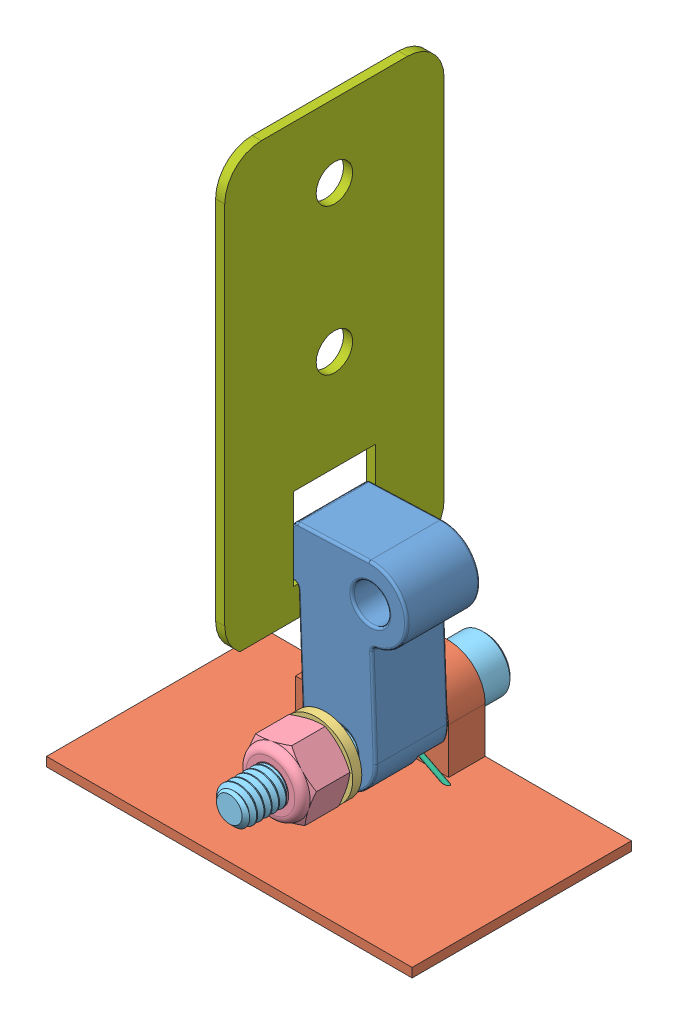
SolidWorks assembly ArrayLock, configuration Default. Lengths in mm.
Overall size (63.5 105.25 45.75).
7 component instances, 7 part files, 13 mates.
Components (placement in the parent):
- ArrayPin(V1)-1: ArrayPin(V1) [Default] at (-53.8648 34.9117 1.7367) x (0.999277 0.038028 0) z (0 0 1) size (25.4 36.51 12.7)
- pinstand-1: pinstand [Default] at (-85.6148 25.3867 -17.3133) size (63.5 15.88 38.1)
- pt25xpt5washer-1: pt25xpt5washer [Default] at (-53.8648 34.9117 5.7161) x (-0.497305 -0.867576 0) z (0 0 -1) size (12.7 12.7 1.59)
- 90630A110_High-Strength Steel Nylon-Insert Locknut-1: 90630A110_High-Strength Steel Nylon-Insert Locknut [90630A110] at (-53.8648 34.9117 5.7161) x (-0.951087 0.308922 0) z (0.308922 0.951087 0) size (11.11 8.31 12.83)
- 90128A251_Zinc-Plated Alloy Steel Socket Head Screw-2: 90128A251_Zinc-Plated Alloy Steel Socket Head Screw [90128A251] at (-53.8648 34.9117 -1.4383) x (-0.999187 0.040322 0) z (0 0 -1) size (9.53 9.53 45.23)
- 9271K274_Torsion Spring-1: 9271K274_Torsion Spring [9271K274] at (-53.9119 35.5553 -9.8575) x (0.001959 -0.028703 -0.999586) z (0.884392 -0.466499 0.015129) size (5.5 24.74 42.2)
- Snapmount-1: Snapmount [Default] at (-63.3898 48.5361 13.643) x (0 0 -1) z (1 0 0) size (38.1 76.2 1.59)
Mates (geometry in assembly coordinates):
- Concentric3: concentric anti-aligned: cylinder of ArrayPin(V1)-1 through (-53.8648 34.9117 -10.9633) axis (0 0 -1) radius 3.175; cylinder of pt25xpt5washer-1 through (-53.8648 34.9117 4.1286) axis (0 0 1) radius 3.175
- Concentric5: concentric anti-aligned: cylinder of pt25xpt5washer-1 through (-53.8648 34.9117 4.1286) axis (0 0 1) radius 6.35; cylinder of 90630A110_High-Strength Steel Nylon-Insert Locknut-1 through (-53.8648 34.9117 12.4069) axis (0 0 -1) radius 2.6987
- Coincident17: coincident anti-aligned: plane of ArrayPin(V1)-1 through (-48.4249 58.9485 -10.9633) normal (0 0 -1); plane of pinstand-1 through (-53.8648 34.9117 -10.9633) normal (0 0 1)
- Concentric8: concentric anti-aligned: cylinder of ArrayPin(V1)-1 through (-53.8648 34.9117 -10.9633) axis (0 0 1) radius 3.175; cylinder of pinstand-1 through (-53.8648 34.9117 -10.9633) axis (0 0 -1) radius 3.175
- Parallel3: parallel anti-aligned: plane of ArrayPin(V1)-1 through (-59.6191 60.8821 -6.2008) normal (0.038028 -0.999277 0); plane of 9271K274_Torsion Spring-1 through (-59.2372 60.8654 -6.5818) normal (-0.038028 0.999277 0)
- Distance4: distance = 0.0312 mm anti-aligned: plane of 9271K274_Torsion Spring-1 through (-59.2372 60.8654 -6.5818) normal (-0.038028 0.999277 0); plane of ArrayPin(V1)-1 through (-59.6191 60.8821 -6.2008) normal (0.038028 -0.999277 0)
- Tangent23: tangent anti-aligned: plane of ArrayPin(V1)-1 through (-53.8648 34.9117 -6.2008) normal (0 0 -1); cylinder of 9271K274_Torsion Spring-1 through (-59.2372 60.8654 -6.5818) axis (0.038028 -0.999277 0) radius 0.381
- Tangent24: tangent anti-aligned: plane of ArrayPin(V1)-1 through (-58.7483 38.001 -6.2008) normal (0.999277 0.038028 0); cylinder of 9271K274_Torsion Spring-1 through (-59.2372 60.8654 -6.5818) axis (0.038028 -0.999277 0) radius 0.381
- Concentric10: concentric aligned: cylinder of pinstand-1 through (-53.8648 34.9117 -10.9633) axis (0 0 -1) radius 3.175; cylinder of 90128A251_Zinc-Plated Alloy Steel Socket Head Screw-2 through (-53.8648 34.9117 -23.6633) axis (0 0 -1) radius 3.175
- Coincident22: coincident anti-aligned: plane of pinstand-1 through (-85.6148 25.3867 -17.3133) normal (0 0 -1); plane of 90128A251_Zinc-Plated Alloy Steel Socket Head Screw-2 through (-54.0376 30.629 -17.3133) normal (0 0 1)
- Coincident23: coincident anti-aligned: plane of pt25xpt5washer-1 through (-53.8648 34.9117 5.7161) normal (0 0 1); plane of 90630A110_High-Strength Steel Nylon-Insert Locknut-1 through (-60.1403 33.5772 5.7161) normal (0 0 -1)
- Coincident24: coincident anti-aligned: plane of pinstand-1 through (-61.8023 59.9823 -17.3133) normal (-1 0 0); plane of Snapmount-1 through (-61.8023 118.3861 7.293) normal (1 0 0)
- Coincident27: coincident anti-aligned: plane of ArrayPin(V1)-1 through (-48.4249 58.9485 1.7367) normal (0 0 1); plane of Snapmount-1 through (-61.8023 54.8861 1.7367) normal (0 0 -1)
